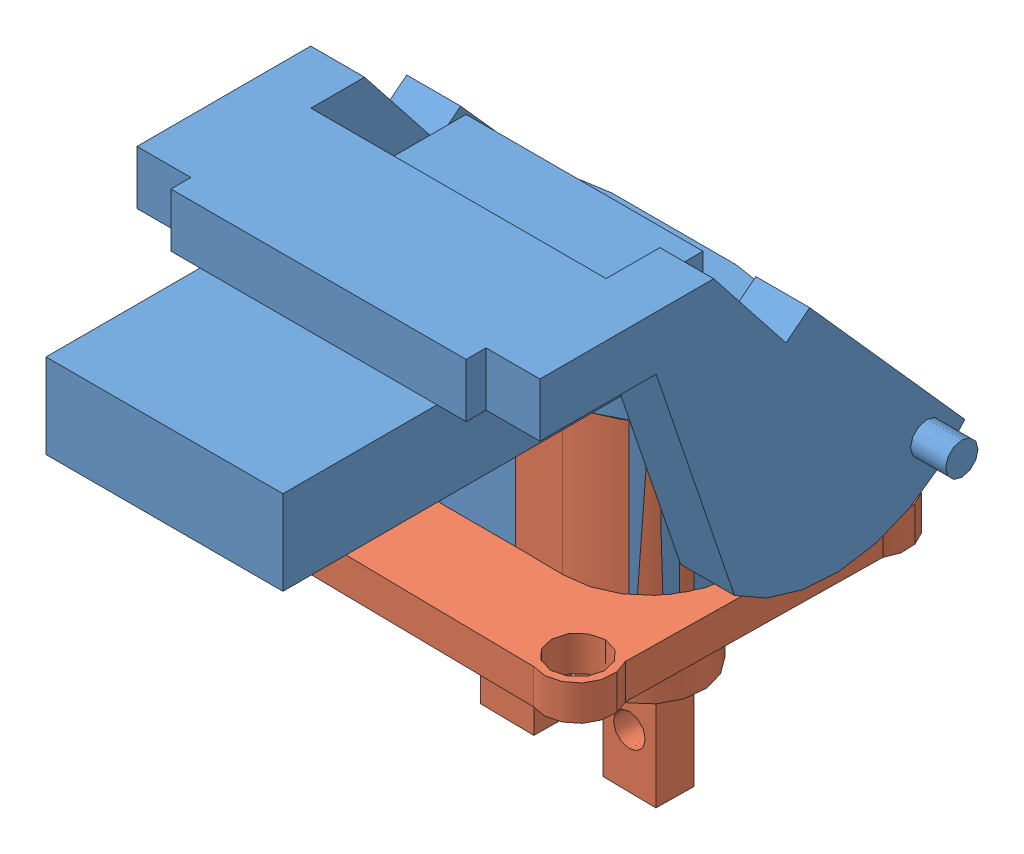
SolidWorks assembly PUTM-H-TS-BOX-main_connector, configuration Domyślna. Lengths in mm.
Overall size (87.87 100.7 112.47).
2 component instances, 2 part files, 2 mates.
Components (placement in the parent):
- PUTM-H-connector_female-1: PUTM-H-connector_female [Domyślna] at (-60.9888 -3.8752 130.0789) size (87.87 59.7 111.2)
- PUTM-H-connector_male-1: PUTM-H-connector_male [Domyślna] at (-123.4643 -44.3752 49.7757) x (-0.999897 0 -0.01432) z (0.01432 0 -0.999897) size (74.6 75 66.8)
Mates (geometry in assembly coordinates):
- Wspólnie1: coincident anti-aligned: plane of PUTM-H-connector_female-1 through (-116.5408 -37.8752 56.5947) normal (0 -1 0); plane of PUTM-H-connector_male-1 through (-78.4543 -37.8752 85.7431) normal (0 1 0)
- Koncentryczne1: concentric aligned: circle of PUTM-H-connector_female-1; cylinder of PUTM-H-connector_male-1 through (-116.5408 -4.8752 56.5947) axis (0 -1 0) radius 4
